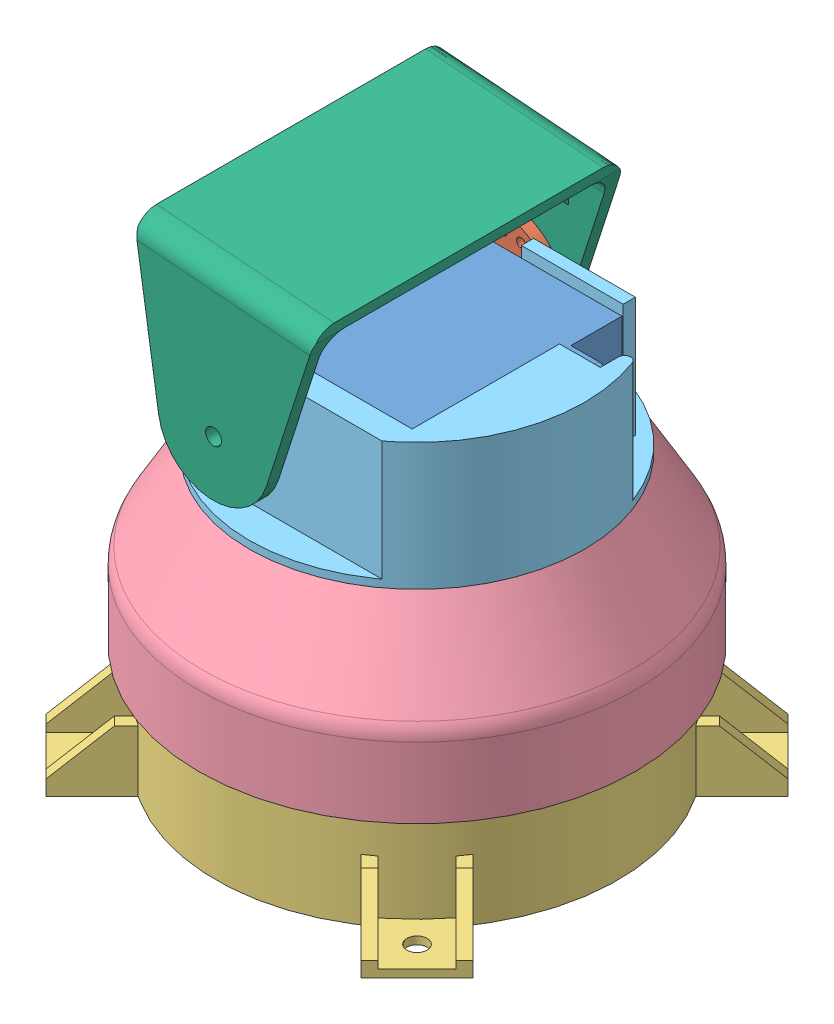
SolidWorks assembly PanTilt, configuration Default. Lengths in mm.
Overall size (85.8 95.99 85.8).
8 component instances, 6 part files, 25 mates.
Components (placement in the parent):
- D3015-3: D3015 [Default] at (30.3827 28.9681 43.0424) x (0 0 1) z (0 -1 0) size (56.5 20 45.8)
- RoundServoHorn-1: RoundServoHorn [Default] at (30.3827 54.5181 43.0424) x (0 0 -1) z (0 1 0) size (20.8 20.8 5.55)
- PanBase-1: PanBase [Default] at (30.3827 36.4681 43.0424) x (0 0 1) z (0 -1 0) size (83.86 83.86 30.15)
- PanTop-2: PanTop [Default] at (30.3827 56.7681 43.0424) x (0 0 -1) z (0 1 0) size (85.8 85.8 32.8)
- TiltBase-1: TiltBase [Default] at (30.3827 59.2681 43.0424) x (0 0 -1) z (0 1 0) size (65.8 65.8 25)
- D3015-4: D3015 [Default] at (20.3827 62.3681 33.4224) size (56.5 20 45.8)
- RoundServoHorn-2: RoundServoHorn [Default] at (21.4876 81.1727 7.5724) x (-0.078569 -0.996909 0) z (0 0 -1) size (20.8 20.8 5.55)
- TiltTop-1: TiltTop [Default] at (21.4876 81.1727 5.3224) x (-0.078569 -0.996909 0) z (0 0 -1) size (39.55 35 60.85)
Mates (geometry in assembly coordinates):
- InPlace3: in place: plane of D3015-3 through (10.3827 36.4681 15.5424) normal (0 -1 0); plane of ? through (0 36.4681 0) normal (0 -1 0); moOrthogonalPlaneRef_w of D3015-3 through (10.3827 36.4681 15.5424) normal (0 -1 0); plane of ? through (0 36.4681 0) normal (0 0 -1); plane of D3015-3 through (10.3827 36.4681 15.5424) normal (0 -1 0); plane of ? through (0 36.4681 0) normal (-1 0 0); plane of D3015-3 through (10.3827 36.4681 15.5424) normal (0 -1 0); unknown of PanBase-1
- Coincident7: coincident aligned: plane of D3015-3; plane of PanBase-1
- Coincident8: coincident aligned: moOrthogonalPlaneRef_w of D3015-3 through (30.3827 36.4681 43.0424) normal (-1 0 0); plane of PanBase-1 through (30.3827 36.4681 43.0424) normal (-1 0 0)
- Coincident9: coincident anti-aligned: moOrthogonalPlaneRef_w of D3015-3 through (30.3827 36.4681 43.0424) normal (0 0 -1); plane of PanBase-1 through (30.3827 36.4681 43.0424) normal (0 0 1)
- InPlace5: in place: plane of D3015-3 through (20.3827 54.5181 33.4224) normal (0 1 0); plane of ? through (0 54.5181 0) normal (0 1 0); plane of D3015-3 through (20.3827 54.5181 33.4224) normal (0 1 0); plane of ? through (0 54.5181 0) normal (0 0 -1); plane of D3015-3 through (20.3827 54.5181 33.4224) normal (0 1 0); plane of ? through (0 54.5181 0) normal (1 0 0); plane of D3015-3 through (20.3827 54.5181 33.4224) normal (0 1 0); unknown of RoundServoHorn-1
- Coincident5: coincident aligned: plane of D3015-3; plane of RoundServoHorn-1
- Coincident6: coincident aligned: moOrthogonalPlaneRef_w of D3015-3 through (30.3827 54.5181 43.0424) normal (-1 0 0); plane of RoundServoHorn-1 through (30.3827 54.5181 43.0424) normal (-1 0 0)
- Coincident7: coincident anti-aligned: moOrthogonalPlaneRef_w of D3015-3 through (30.3827 54.5181 43.0424) normal (0 0 1); plane of RoundServoHorn-1 through (30.3827 54.5181 43.0424) normal (0 0 -1)
- InPlace6: in place: plane of RoundServoHorn-1 through (20.3827 56.7681 33.4224) normal (0 1 0); plane of ? through (0 56.7681 0) normal (0 1 0); plane of RoundServoHorn-1 through (20.3827 56.7681 33.4224) normal (0 1 0); plane of ? through (0 56.7681 0) normal (0 0 -1); plane of RoundServoHorn-1 through (20.3827 56.7681 33.4224) normal (0 1 0); plane of ? through (0 56.7681 0) normal (1 0 0); plane of RoundServoHorn-1 through (20.3827 56.7681 33.4224) normal (0 1 0); unknown of PanTop-2
- Coincident8: coincident aligned: plane of RoundServoHorn-1; plane of PanTop-2
- Coincident9: coincident aligned: moOrthogonalPlaneRef_w of RoundServoHorn-1 through (30.3827 56.7681 43.0424) normal (-1 0 0); plane of PanTop-2 through (30.3827 56.7681 43.0424) normal (-1 0 0)
- Coincident10: coincident anti-aligned: moOrthogonalPlaneRef_w of RoundServoHorn-1 through (30.3827 56.7681 43.0424) normal (0 0 1); plane of PanTop-2 through (30.3827 56.7681 43.0424) normal (0 0 -1)
- Concentric1: concentric aligned: cylinder of D3015-4 through (10.7627 72.3681 7.8724) axis (0 0 1) radius 2.875; cylinder of RoundServoHorn-2 through (10.7627 72.3681 7.8724) axis (0 0 1) radius 2.95
- Coincident12: coincident anti-aligned: plane of D3015-4 through (10.7627 72.3681 7.8724) normal (0 0 -1); plane of RoundServoHorn-2 through (10.7627 72.3681 7.8724) normal (0 0 1)
- InPlace7: in place: plane of PanTop-2 through (20.3827 59.2681 33.4224) normal (0 1 0); plane of ? through (0 59.2681 0) normal (0 1 0); plane of PanTop-2 through (20.3827 59.2681 33.4224) normal (0 1 0); plane of ? through (0 59.2681 0) normal (0 0 -1); plane of PanTop-2 through (20.3827 59.2681 33.4224) normal (0 1 0); plane of ? through (0 59.2681 0) normal (1 0 0); plane of PanTop-2 through (20.3827 59.2681 33.4224) normal (0 1 0); unknown of TiltBase-1
- Coincident13: coincident aligned: plane of PanTop-2; plane of TiltBase-1
- Coincident14: coincident aligned: moOrthogonalPlaneRef_w of PanTop-2 through (30.3827 59.2681 43.0424) normal (-1 0 0); plane of TiltBase-1 through (30.3827 59.2681 43.0424) normal (-1 0 0)
- Coincident15: coincident anti-aligned: moOrthogonalPlaneRef_w of PanTop-2 through (30.3827 59.2681 43.0424) normal (0 0 1); plane of TiltBase-1 through (30.3827 59.2681 43.0424) normal (0 0 -1)
- Distance5: distance = 0.1 mm anti-aligned: plane of TiltBase-1 through (20.3827 62.2681 33.4224) normal (0 1 0); plane of D3015-4 through (20.3827 62.3681 33.4224) normal (0 -1 0)
- Coincident18: coincident anti-aligned: plane of TiltBase-1 through (-0.1173 -20.0988 25.9224) normal (0 0 -1); plane of D3015-4 through (-7.1173 82.3681 25.9224) normal (0 0 1)
- Distance7: distance = 0.5 mm anti-aligned: plane of TiltBase-1 through (-0.1173 -20.0988 35.9224) normal (1 0 0); plane of D3015-4 through (0.3827 82.3681 53.6724) normal (-1 0 0)
- InPlace8: in place: plane of ? through (10.7627 72.3681 5.3224) normal (0 0 -1); plane of ? through (0 0 5.3224) normal (0 0 -1); plane of ? through (10.7627 72.3681 5.3224) normal (0 0 -1); plane of ? through (0 0 5.3224) normal (0 1 0); plane of ? through (10.7627 72.3681 5.3224) normal (0 0 -1); plane of ? through (0 0 5.3224) normal (-1 0 0); plane of RoundServoHorn-2 through (10.7627 72.3681 5.3224) normal (0 0 -1); unknown of TiltTop-1
- Coincident19: coincident aligned: plane of RoundServoHorn-2; plane of TiltTop-1
- Coincident20: coincident aligned: moOrthogonalPlaneRef_w of RoundServoHorn-2; plane of TiltTop-1 through (21.4876 81.1727 5.3224) normal (-0.996909 0.078569 0)
- Coincident21: coincident anti-aligned: moOrthogonalPlaneRef_w of RoundServoHorn-2; plane of TiltTop-1 through (21.4876 81.1727 5.3224) normal (-0.078569 -0.996909 0)
